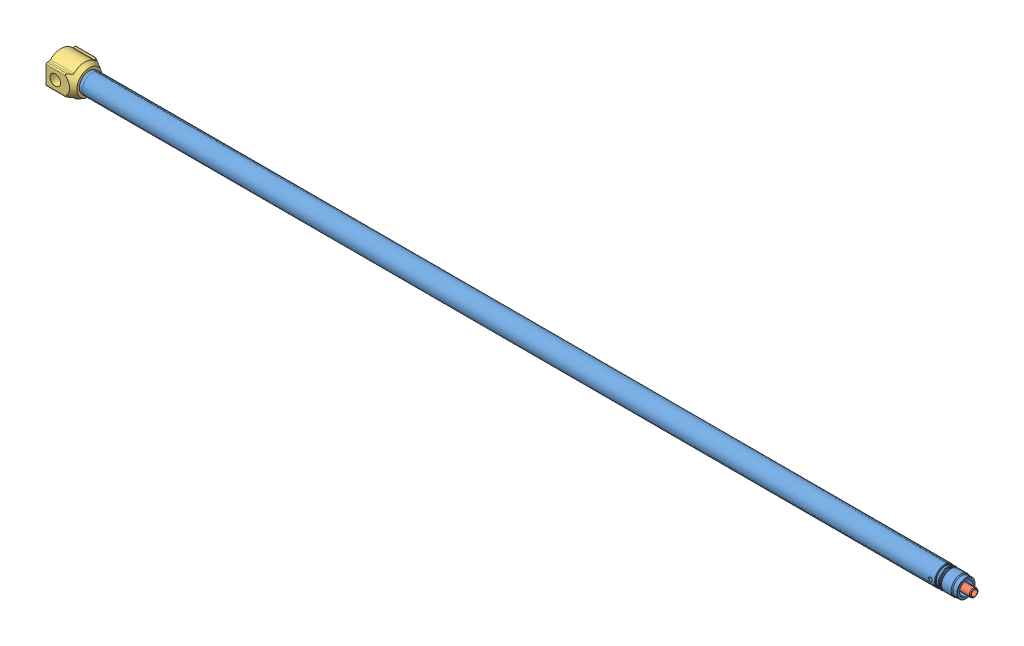
SolidWorks assembly 6344571, configuration Default. Lengths in mm.
Overall size (2265 75 75).
4 component instances, 4 part files, 16 mates.
Components (placement in the parent):
- 6344572-1: 6344572 [Default] at (42 0 0) size (2180 50 50)
- 6344573-1: 6344573 [Default] at (34 0 0) size (2208 20 20)
- 6304259-1: 6304259 [Default] at origin size (70 75 75)
- 6381013-1: 6381013 [Default] at origin (suppressed, hidden)
Mates (geometry in assembly coordinates):
- Coincident3: coincident aligned: plane of 6344573-1 through (34 0 0) normal (0 1 0); plane of assembly through (0 0 0) normal (0 1 0)
- Coincident5: coincident aligned: plane of 6344572-1 through (42 0 0) normal (0 1 0); plane of assembly through (0 0 0) normal (0 1 0)
- Concentric4: concentric aligned: cylinder of 6344572-1 through (42 0 0) axis (-1 0 0) radius 25; cylinder of 6304259-1 through (-65.5921 0 0) axis (-1 0 0) radius 37.5
- Coincident6: coincident anti-aligned: plane of 6344572-1 through (47 24 0) normal (-1 0 0); plane of 6304259-1 through (47 31 0) normal (1 0 0)
- Parallel1: parallel aligned: plane of 6344572-1 through (42 0 0) normal (0 1 0); plane of assembly through (0 0 0) normal (0 1 0)
- Coincident7: coincident: point of 6304259-1
- Parallel2: parallel aligned: plane of 6304259-1 through (0 0 0) normal (0 0 1); plane of assembly through (0 0 0) normal (0 0 1)
- Coincident8: coincident anti-aligned: plane of 6344573-1 through (34 10 0) normal (-1 0 0); plane of 6304259-1 through (34 10 0) normal (1 0 0)
- Concentric5: concentric aligned: cylinder of 6344573-1 through (34 0 0) axis (-1 0 0) radius 10; cylinder of 6304259-1 through (-65.5921 0 0) axis (-1 0 0) radius 10
- Concentric6: concentric aligned: cylinder of 6344572-1 through (42 0 0) axis (-1 0 0) radius 24; cylinder of assembly through (-65.5921 0 0) axis (-1 0 0) radius 24
- Coincident9: coincident anti-aligned: plane of 6344572-1 through (47 24 0) normal (-1 0 0); plane of assembly through (47 31 0) normal (1 0 0)
- Coincident10: coincident: plane of 6381013-1; plane of assembly through (0 0 0) normal (0 0 1)
- Coincident11: coincident: plane of 6381013-1; plane of assembly through (0 0 0) normal (0 0 1)
- Coincident12: coincident: plane of 6381013-1; plane of assembly through (0 0 0) normal (0 1 0)
- Coincident13: coincident: plane of 6381013-1; plane of assembly through (0 0 0) normal (1 0 0)
- Parallel3: parallel aligned: plane of 6344573-1 through (34 0 0) normal (0 0 1); plane of assembly through (0 0 0) normal (0 0 1)
